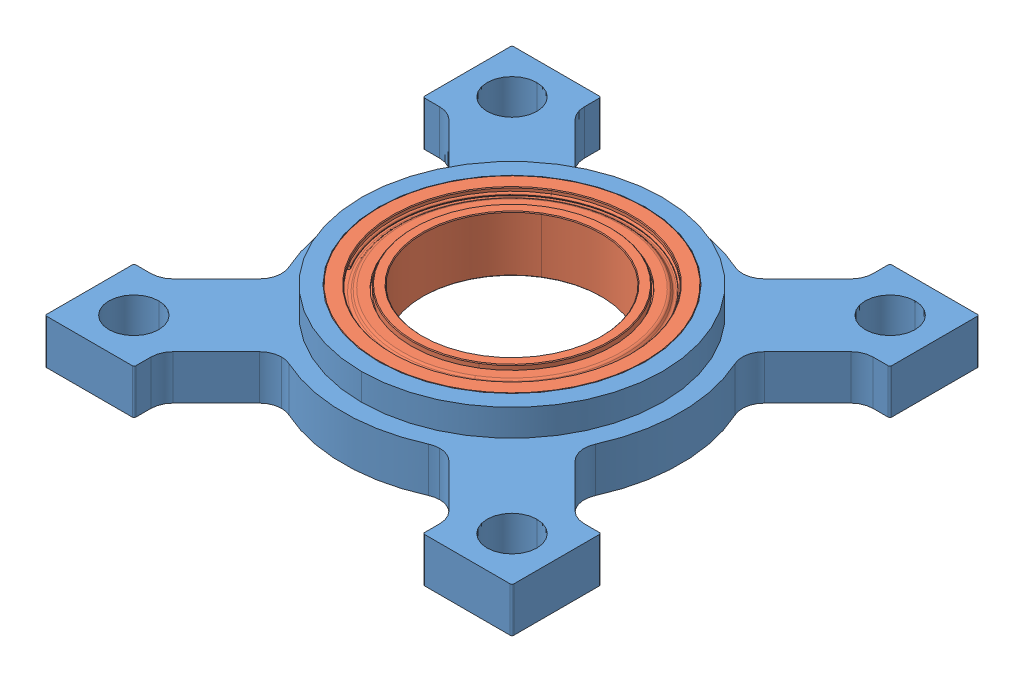
SolidWorks assembly .5in pillow block bearing, configuration Default. Lengths in mm.
Overall size (33.27 5.09 33.27).
2 component instances, 2 part files, 0 mates.
Components (placement in the parent):
- 535118.STEP-1: 535118.STEP [Default] at (4.5754 14.638 29.8068) size (33.27 5.08 33.27)
- 535026.STEP-1: 535026.STEP [Default] at (4.5754 17.74 29.8068) x (0.853345 0 -0.521347) z (0.521347 0 0.853345) size (19.05 3.97 19.05)
